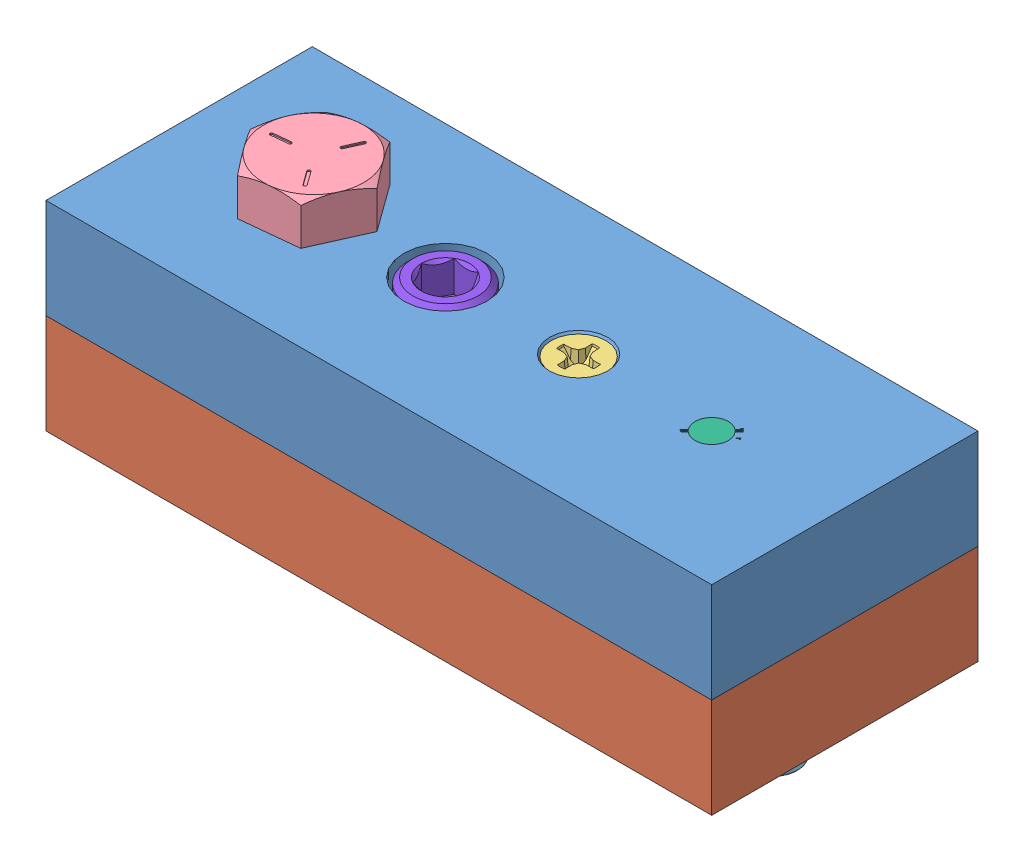
SolidWorks assembly Assem1, configuration Default. Lengths in mm.
Overall size (127 65.82 50.8).
9 component instances, 9 part files, 18 mates.
Components (placement in the parent):
- 0.75x2.00x5.00_in_Rect.-1: 0.75x2.00x5.00_in_Rect. [Default] at origin size (127 19.05 50.8)
- 0.75x2.00x5.00_in_Rect. - Copy-1: 0.75x2.00x5.00_in_Rect. - Copy [Default] at (0 -19.05 0) size (127 19.05 50.8)
- 90273A299_ZINC-PLATED STL FLAT HEAD PHIL MACHINE SCREW-1: 90273A299_ZINC-PLATED STL FLAT HEAD PHIL MACHINE SCREW [90273A299] at (76.2 15.3173 25.4) x (-0.999709 0 0.024127) z (0 1 0) size (10.46 10.46 38.63)
- 91247A721_MEDIUM-STRG GRADE 5 ZINC-PLTD STL CAP SCREW-1: 91247A721_MEDIUM-STRG GRADE 5 ZINC-PLTD STL CAP SCREW [91247A721] at (25.7786 -5.5563 25.5169) x (0 -1 0) z (-0.103504 0 -0.994629) size (65.82 22 19.05)
- 98335A049_ZINC-PLATED STEEL REUSABLE COTTER PIN-1: 98335A049_ZINC-PLATED STEEL REUSABLE COTTER PIN [98335A049] at (87.1857 -24.3681 25.4) x (0 -1 0) z (-1 0 0) size (1.59 9.52 34.92)
- 98306A165_STEEL CLEVIS PIN-1: 98306A165_STEEL CLEVIS PIN [98306A165] at (101.6 -5.715 25.4) x (-1 0 0) z (0 1 0) size (9.65 9.65 46.99)
- 96765A160_BLACK-OXIDE 18-8 STAINLESS STEEL FLAT WASHER-1: 96765A160_BLACK-OXIDE 18-8 STAINLESS STEEL FLAT WASHER [96765A160] at (25.7786 -20.8788 25.5169) x (0 0 1) z (-1 0 0) size (31.75 1.83 31.75)
- 91251A626_BLACK-OXIDE ALLOY STEEL SOCKET HEAD CAP SCREW (1)-1: 91251A626_BLACK-OXIDE ALLOY STEEL SOCKET HEAD CAP SCREW (1) [91251A626] at (50.8 -22.225 25.4) x (0.002946 0 0.999996) z (0 -1 0) size (14.29 14.29 41.9)
- 95462A033_GRADE 5 STEEL HEX NUT-1: 95462A033_GRADE 5 STEEL HEX NUT [95462A033] at (25.7837 -26.4351 25.5177) x (-0.960893 0 -0.276919) z (0 -1 0) size (19.05 22 14.07)
Mates (geometry in assembly coordinates):
- Coincident1: coincident anti-aligned: plane of 0.75x2.00x5.00_in_Rect.-1 through (0 0 50.8) normal (0 -1 0); plane of 0.75x2.00x5.00_in_Rect. - Copy-1 through (0 0 50.8) normal (0 1 0)
- Coincident2: coincident aligned: plane of 0.75x2.00x5.00_in_Rect.-1 through (0 0 50.8) normal (0 0 1); plane of 0.75x2.00x5.00_in_Rect. - Copy-1 through (0 -19.05 50.8) normal (0 0 1)
- Coincident3: coincident aligned: plane of 0.75x2.00x5.00_in_Rect.-1 through (0 0 50.8) normal (-1 0 0); plane of 0.75x2.00x5.00_in_Rect. - Copy-1 through (0 -19.05 50.8) normal (-1 0 0)
- Tangent2: tangent: cylinder of 0.75x2.00x5.00_in_Rect.-1 through (25.4 19.05 25.4) axis (0 1 0) radius 6.7462; curve of 91247A721_MEDIUM-STRG GRADE 5 ZINC-PLTD STL CAP SCREW-1
- Coincident4: coincident anti-aligned: plane of 0.75x2.00x5.00_in_Rect.-1 through (0 19.05 50.8) normal (0 1 0); plane of 91247A721_MEDIUM-STRG GRADE 5 ZINC-PLTD STL CAP SCREW-1 through (19.323 19.05 16.6122) normal (0 -1 0)
- Coincident5: coincident aligned: cone of 0.75x2.00x5.00_in_Rect.-1 through (76.2 19.05 25.4) axis (0 -1 0); cone of 90273A299_ZINC-PLATED STL FLAT HEAD PHIL MACHINE SCREW-1 through (76.2 18.6701 25.4) axis (0 -1 0)
- Concentric1: concentric anti-aligned: cylinder of 0.75x2.00x5.00_in_Rect.-1 through (101.6 19.05 25.4) axis (0 1 0) radius 3.175; cylinder of 98306A165_STEEL CLEVIS PIN-1 through (101.6 16.51 25.4) axis (0 -1 0) radius 3.175
- Coincident6: coincident aligned: plane of 0.75x2.00x5.00_in_Rect.-1 through (0 19.05 50.8) normal (0 1 0); plane of 98306A165_STEEL CLEVIS PIN-1 through (101.6 19.05 25.4) normal (0 1 0)
- Concentric2: concentric aligned: cylinder of 98335A049_ZINC-PLATED STEEL REUSABLE COTTER PIN-1 through (117.3482 -24.3681 25.4) axis (-1 0 0) radius 0.7937; cylinder of 98306A165_STEEL CLEVIS PIN-1 through (106.426 -24.3681 25.4) axis (-1 0 0) radius 1.1906
- Concentric3: concentric aligned: cylinder of 98335A049_ZINC-PLATED STEEL REUSABLE COTTER PIN-1 through (117.3482 -24.3681 25.4) axis (-1 0 0) radius 0.7937; cylinder of 98306A165_STEEL CLEVIS PIN-1 through (106.426 -24.3681 25.4) axis (-1 0 0) radius 1.1906
- Lock1: lock: unknown of 98335A049_ZINC-PLATED STEEL REUSABLE COTTER PIN-1; unknown of 98306A165_STEEL CLEVIS PIN-1
- Coincident9: coincident anti-aligned: plane of 0.75x2.00x5.00_in_Rect. - Copy-1 through (0 -19.05 50.8) normal (0 -1 0); plane of 96765A160_BLACK-OXIDE 18-8 STAINLESS STEEL FLAT WASHER-1 through (25.7786 -19.05 25.5169) normal (0 1 0)
- Concentric4: concentric anti-aligned: cylinder of 0.75x2.00x5.00_in_Rect. - Copy-1 through (50.8 0 25.4) axis (0 1 0) radius 3.9688; cylinder of 91251A626_BLACK-OXIDE ALLOY STEEL SOCKET HEAD CAP SCREW (1)-1 through (50.8 9.525 25.4) axis (0 -1 0) radius 4.7625
- Coincident11: coincident anti-aligned: plane of 0.75x2.00x5.00_in_Rect.-1 through (55.7022 9.525 25.4) normal (0 1 0); plane of 91251A626_BLACK-OXIDE ALLOY STEEL SOCKET HEAD CAP SCREW (1)-1 through (50.8 9.525 25.4) normal (0 -1 0)
- Tangent11: tangent: face of 91247A721_MEDIUM-STRG GRADE 5 ZINC-PLTD STL CAP SCREW-1; edge_curve of ?
- Coincident12: coincident anti-aligned: plane of 96765A160_BLACK-OXIDE 18-8 STAINLESS STEEL FLAT WASHER-1 through (25.7786 -20.8788 25.5169) normal (0 -1 0); plane of 95462A033_GRADE 5 STEEL HEX NUT-1 through (36.459 -20.8788 22.8711) normal (0 1 0)
- Concentric7: concentric anti-aligned: line of 91247A721_MEDIUM-STRG GRADE 5 ZINC-PLTD STL CAP SCREW-1 through (25.7786 -6.35 25.5169) axis (0 -1 0); cylinder of 96765A160_BLACK-OXIDE 18-8 STAINLESS STEEL FLAT WASHER-1 through (25.7786 -20.8788 25.5169) axis (0 1 0) radius 6.7437
- Coincident13: coordinate: point of 0.75x2.00x5.00_in_Rect.-1
